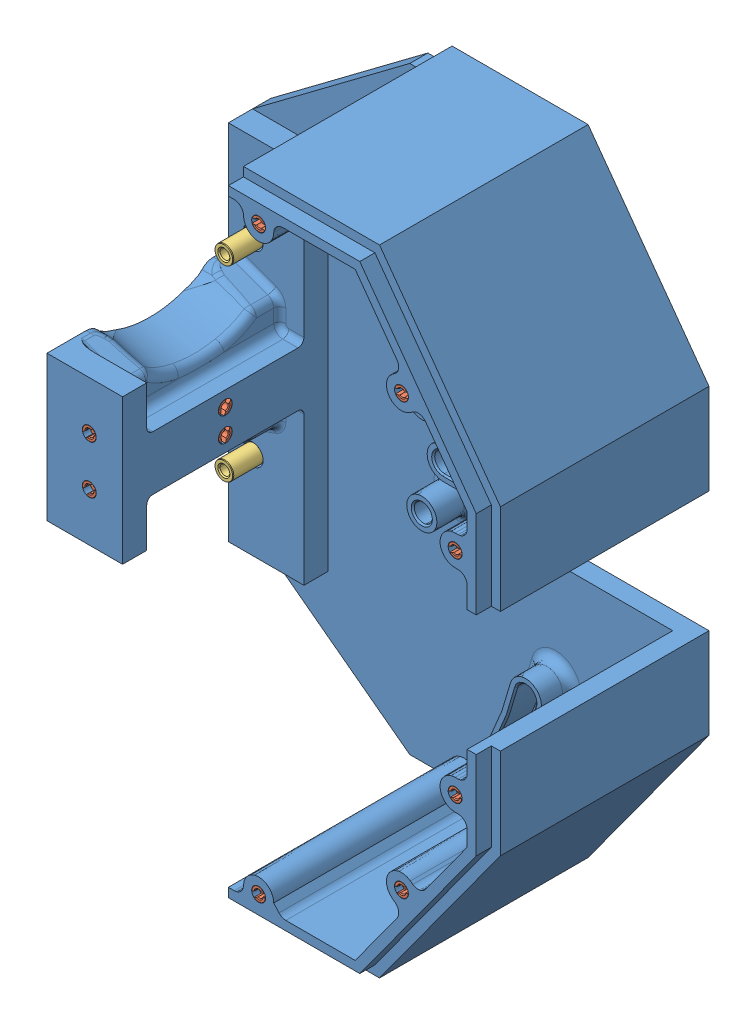
SolidWorks assembly Assieme_Case_sx, configuration Default. Lengths in mm.
Overall size (167.73 210 74).
13 component instances, 3 part files, 26 mates.
Components (placement in the parent):
- Case_sx_v5-1: Case_sx_v5 [Default] at origin size (167.73 210 74)
- Grano_filettato_ENT3_6-1: Grano_filettato_ENT3_6 [Default] at (62 96 31) size (5 5 6)
- Grano_filettato_ENT3_6-20: Grano_filettato_ENT3_6 [Default] at (109.2647 71.1343 31) x (0.987351 0.158553 0) z (0 0 1) size (5 5 6)
- Grano_filettato_ENT3_6-22: Grano_filettato_ENT3_6 [Default] at (127 35 31) x (0.959125 0.282984 0) z (0 0 1) size (5 5 6)
- Grano_filettato_ENT3_6-24: Grano_filettato_ENT3_6 [Default] at (127 -35 31) x (0.928571 0.371154 0) z (0 0 1) size (5 5 6)
- Grano_filettato_ENT3_6-26: Grano_filettato_ENT3_6 [Default] at (109.2647 -71.1343 31) x (0.906989 0.421154 0) z (0 0 1) size (5 5 6)
- Grano_filettato_ENT3_6-28: Grano_filettato_ENT3_6 [Default] at (62 -96 31) x (0.902849 0.429957 0) z (0 0 1) size (5 5 6)
- Grano_filettato_ENT3_6-30: Grano_filettato_ENT3_6 [Default] at (6 8 31) x (0.823258 0.567667 0) z (0 0 1) size (5 5 6)
- Grano_filettato_ENT3_6-32: Grano_filettato_ENT3_6 [Default] at (6 -8 31) x (0.744275 0.667874 0) z (0 0 1) size (5 5 6)
- Grano_filettato_ENT3_6-34: Grano_filettato_ENT3_6 [Default] at (14 4 0) x (0 0.852489 -0.522745) z (1 0 0) size (5 5 6)
- Grano_filettato_ENT3_6-36: Grano_filettato_ENT3_6 [Default] at (14 -4 0) x (0 0.932569 -0.360992) z (1 0 0) size (5 5 6)
- Grano_MSTH6_20-1: Grano_MSTH6_20 [Default] at (0 30.95 -26.5) x (0 0 -1) z (-1 0 0) size (20 6 5.85)
- Grano_MSTH6_20-2: Grano_MSTH6_20 [Default] at (0 -30.95 -26.5) x (0 0 -1) z (-1 0 0) size (20 6 5.85)
Mates (geometry in assembly coordinates):
- Concentrico1: concentric anti-aligned: cylinder of Case_sx_v5-1 through (62 96 19) axis (0 0 1) radius 2.3; cylinder of ENT3_6-1 through (62 96 28) axis (0 0 -1) radius 2.5
- Coincidente1: coincident aligned: plane of Case_sx_v5-1 through (0 0 34) normal (0 0 1); plane of ENT3_6-1 through (62 96 34) normal (0 0 1)
- Concentrico12: concentric anti-aligned: cylinder of Case_sx_v5-1 through (109.2647 71.1343 19) axis (0 0 1) radius 2.3; cylinder of ENT3_6-20 through (109.2647 71.1343 28) axis (0 0 -1) radius 2.5
- Coincidente11: coincident aligned: plane of Case_sx_v5-1 through (0 0 34) normal (0 0 1); plane of ENT3_6-20 through (109.2647 71.1343 34) normal (0 0 1)
- Concentrico13: concentric anti-aligned: cylinder of Case_sx_v5-1 through (127 35 19) axis (0 0 1) radius 2.3; cylinder of ENT3_6-22 through (127 35 28) axis (0 0 -1) radius 2.5
- Coincidente12: coincident aligned: plane of Case_sx_v5-1 through (0 0 34) normal (0 0 1); plane of ENT3_6-22 through (127 35 34) normal (0 0 1)
- Concentrico14: concentric anti-aligned: cylinder of Case_sx_v5-1 through (127 -35 19) axis (0 0 1) radius 2.3; cylinder of ENT3_6-24 through (127 -35 28) axis (0 0 -1) radius 2.5
- Coincidente13: coincident aligned: plane of Case_sx_v5-1 through (0 0 34) normal (0 0 1); plane of ENT3_6-24 through (127 -35 34) normal (0 0 1)
- Concentrico15: concentric anti-aligned: cylinder of Case_sx_v5-1 through (109.2647 -71.1343 19) axis (0 0 1) radius 2.3; cylinder of ENT3_6-26 through (109.2647 -71.1343 28) axis (0 0 -1) radius 2.5
- Coincidente14: coincident aligned: plane of Case_sx_v5-1 through (0 0 34) normal (0 0 1); plane of ENT3_6-26 through (109.2647 -71.1343 34) normal (0 0 1)
- Concentrico16: concentric anti-aligned: cylinder of Case_sx_v5-1 through (62 -96 19) axis (0 0 1) radius 2.3; cylinder of ENT3_6-28 through (62 -96 28) axis (0 0 -1) radius 2.5
- Coincidente15: coincident aligned: plane of Case_sx_v5-1 through (0 0 34) normal (0 0 1); plane of ENT3_6-28 through (62 -96 34) normal (0 0 1)
- Concentrico17: concentric anti-aligned: cylinder of Case_sx_v5-1 through (6 8 24) axis (0 0 1) radius 2.3; cylinder of ENT3_6-30 through (6 8 28) axis (0 0 -1) radius 2.5
- Coincidente16: coincident aligned: plane of Case_sx_v5-1 through (0 0 34) normal (0 0 1); plane of ENT3_6-30 through (6 8 34) normal (0 0 1)
- Concentrico18: concentric anti-aligned: cylinder of Case_sx_v5-1 through (6 -8 24) axis (0 0 1) radius 2.3; cylinder of ENT3_6-32 through (6 -8 28) axis (0 0 -1) radius 2.5
- Coincidente17: coincident aligned: plane of Case_sx_v5-1 through (0 0 34) normal (0 0 1); plane of ENT3_6-32 through (6 -8 34) normal (0 0 1)
- Concentrico19: concentric anti-aligned: cylinder of Case_sx_v5-1 through (11 4 0) axis (1 0 0) radius 2.3; cylinder of ENT3_6-34 through (11 4 0) axis (-1 0 0) radius 2.5
- Coincidente18: coincident aligned: plane of Case_sx_v5-1 through (17 60 34) normal (1 0 0); plane of ENT3_6-34 through (17 4 0) normal (1 0 0)
- Concentrico20: concentric anti-aligned: cylinder of Case_sx_v5-1 through (11 -4 0) axis (1 0 0) radius 2.3; cylinder of ENT3_6-36 through (11 -4 0) axis (-1 0 0) radius 2.5
- Coincidente19: coincident aligned: plane of Case_sx_v5-1 through (17 60 34) normal (1 0 0); plane of ENT3_6-36 through (17 -4 0) normal (1 0 0)
- Concentrico21: concentric anti-aligned: cylinder of Case_sx_v5-1 through (0 30.95 -36.5) axis (0 0 1) radius 3; cylinder of Grano_MSTH6_20-1 through (0 30.95 -36.5) axis (0 0 -1) radius 3
- Coincidente20: coincident anti-aligned: plane of Case_sx_v5-1 through (-2.85 31.8867 -36.5) normal (1 0 0); plane of Grano_MSTH6_20-1 through (-2.85 33.95 -36.5) normal (-1 0 0)
- Coincidente21: coincident anti-aligned: plane of Case_sx_v5-1 through (0 30.95 -36.5) normal (0 0 1); plane of Grano_MSTH6_20-1 through (0 28.4859 -36.5) normal (0 0 -1)
- Concentrico22: concentric anti-aligned: cylinder of Case_sx_v5-1 through (0 -30.95 -36.5) axis (0 0 1) radius 3; cylinder of Grano_MSTH6_20-2 through (0 -30.95 -36.5) axis (0 0 -1) radius 3
- Coincidente22: coincident anti-aligned: plane of Case_sx_v5-1 through (-2.85 -30.0133 -36.5) normal (1 0 0); plane of Grano_MSTH6_20-2 through (-2.85 -27.95 -36.5) normal (-1 0 0)
- Coincidente23: coincident anti-aligned: plane of Case_sx_v5-1 through (0 -30.95 -36.5) normal (0 0 1); plane of Grano_MSTH6_20-2 through (0 -33.4141 -36.5) normal (0 0 -1)
